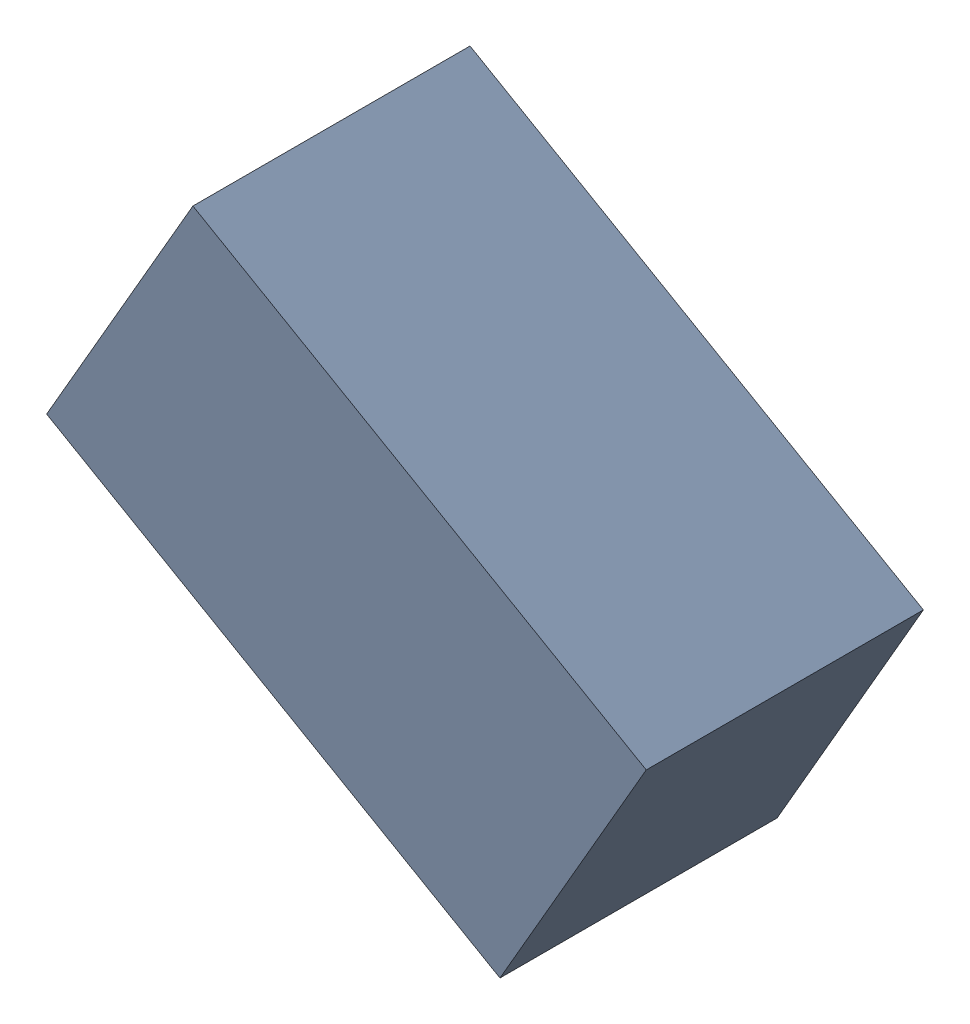
SolidWorks assembly R1_TDA6, configuration Standard. Lengths in mm.
Overall size (1.95 1.67 0.9).
2 component instances, 1 part files, 0 mates.
Components (placement in the parent):
- 885544144-1: 885544144 [Standard] at (-45.2224 21.6649 0) size (1.95 1.67 0.9)
  - Extruded_14-1: Extruded_14 [Standard] at origin size (1.95 1.67 0.9)
